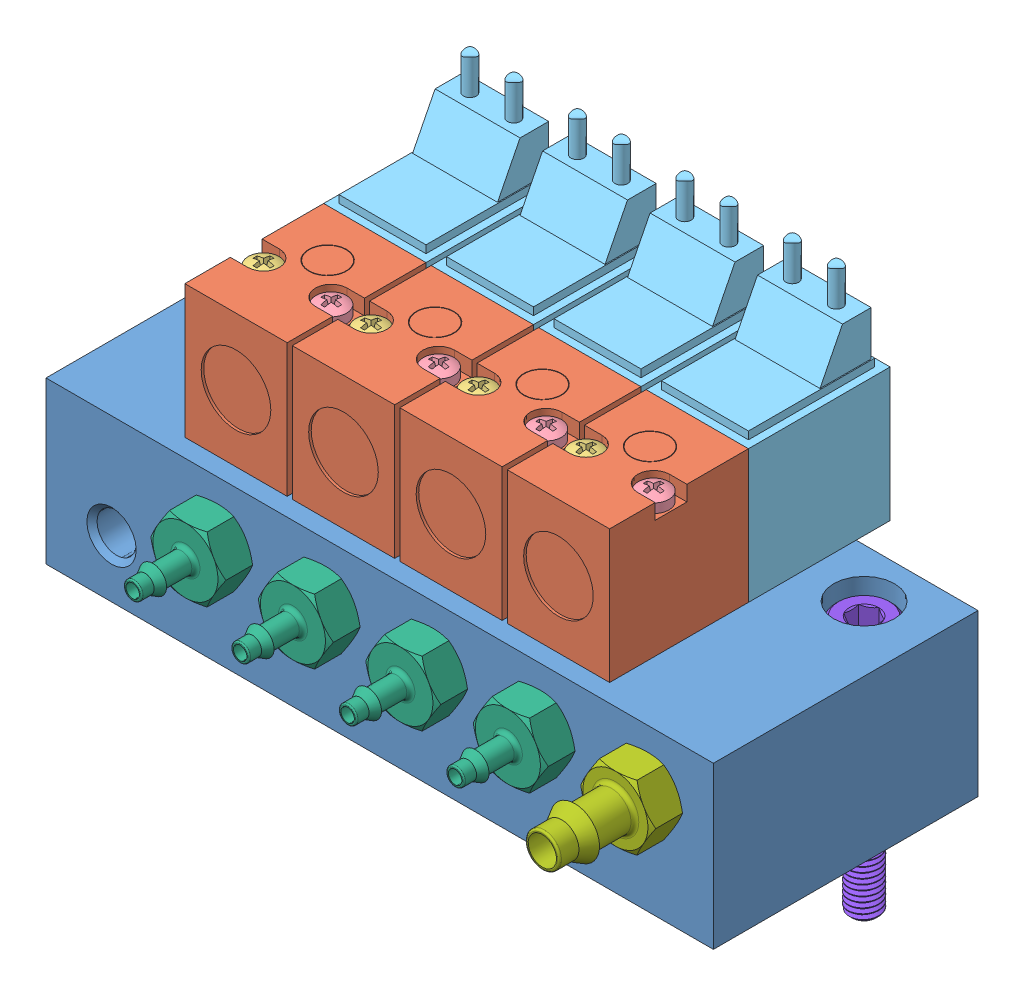
SolidWorks assembly SUB_Solenoid Assembly, configuration Default. Lengths in mm.
Overall size (65.2 48.05 39.48).
28 component instances, 8 part files, 33 mates.
Components (placement in the parent):
- M01_manifold_e10m-04-1: M01_manifold_e10m-04 [Default] at (-10.6613 43.4676 37.3223) x (1 0 0) z (0 -1 0) size (65.2 25.85 15.75)
- M04_valve_e210a-1w012-1: M04_valve_e210a-1w012 [Default] at (6.1387 43.4676 61.4113) x (0 0 -1) z (1 0 0) size (27.4 23.54 10)
  - valve_e210a-1w012_01-1: valve_e210a-1w012_01 [Default] at origin size (15.56 13 10)
  - valve_e210a-1w012_02-1: valve_e210a-1w012_02 [Default] at origin size (3 14.79 3)
  - valve_e210a-1w012_03-1: valve_e210a-1w012_03 [Default] at origin size (3 14.79 3)
  - valve_e210a-1w012_04-1: valve_e210a-1w012_04 [Default] at origin size (13.84 21.54 10)
- M04_valve_e210a-1w012-2: M04_valve_e210a-1w012 [Default] at (16.6387 43.4676 61.4113) x (0 0 -1) z (1 0 0) size (27.4 23.54 10)
  - valve_e210a-1w012_01-1: valve_e210a-1w012_01 [Default] at origin size (15.56 13 10)
  - valve_e210a-1w012_02-1: valve_e210a-1w012_02 [Default] at origin size (3 14.79 3)
  - valve_e210a-1w012_03-1: valve_e210a-1w012_03 [Default] at origin size (3 14.79 3)
  - valve_e210a-1w012_04-1: valve_e210a-1w012_04 [Default] at origin size (13.84 21.54 10)
- M04_valve_e210a-1w012-3: M04_valve_e210a-1w012 [Default] at (27.1387 43.4676 61.4113) x (0 0 -1) z (1 0 0) size (27.4 23.54 10)
  - valve_e210a-1w012_01-1: valve_e210a-1w012_01 [Default] at origin size (15.56 13 10)
  - valve_e210a-1w012_02-1: valve_e210a-1w012_02 [Default] at origin size (3 14.79 3)
  - valve_e210a-1w012_03-1: valve_e210a-1w012_03 [Default] at origin size (3 14.79 3)
  - valve_e210a-1w012_04-1: valve_e210a-1w012_04 [Default] at origin size (13.84 21.54 10)
- M04_valve_e210a-1w012-4: M04_valve_e210a-1w012 [Default] at (37.6387 43.4676 61.4113) x (0 0 -1) z (1 0 0) size (27.4 23.54 10)
  - valve_e210a-1w012_01-1: valve_e210a-1w012_01 [Default] at origin size (15.56 13 10)
  - valve_e210a-1w012_02-1: valve_e210a-1w012_02 [Default] at origin size (3 14.79 3)
  - valve_e210a-1w012_03-1: valve_e210a-1w012_03 [Default] at origin size (3 14.79 3)
  - valve_e210a-1w012_04-1: valve_e210a-1w012_04 [Default] at origin size (13.84 21.54 10)
- M11_11752-5-pkg-2: M11_11752-5-pkg [Default] at (6.1387 38.0176 63.1723) x (0.866025 -0.5 0) z (-0.5 -0.866025 0) size (6.35 12.29 7.33)
- M11_11752-5-pkg-3: M11_11752-5-pkg [Default] at (16.6387 38.0176 63.1723) x (0.866025 -0.5 0) z (-0.5 -0.866025 0) size (6.35 12.29 7.33)
- M11_11752-5-pkg-4: M11_11752-5-pkg [Default] at (37.6387 38.0176 63.1723) x (0.866025 -0.5 0) z (-0.5 -0.866025 0) size (6.35 12.29 7.33)
- M11_11752-5-pkg-5: M11_11752-5-pkg [Default] at (27.1387 38.0176 63.1723) x (0.866025 -0.5 0) z (-0.5 -0.866025 0) size (6.35 12.29 7.33)
- M10_11752-4-pkg-1: M10_11752-4-pkg [Default] at (48.1387 38.0176 66.3473) x (0.866025 0.5 0) z (0.5 -0.866025 0) size (6.35 14.28 7.33)
- 91292A801_18-8 Stainless Steel Socket Head Screw-1: 91292A801_18-8 Stainless Steel Socket Head Screw [91292A801] at (48.1887 29.7076 42.1023) x (1 0 0) z (0 1 0) size (5.5 5.5 25.38)
- 91292A801_18-8 Stainless Steel Socket Head Screw-2: 91292A801_18-8 Stainless Steel Socket Head Screw [91292A801] at (-4.3113 29.7076 42.1023) x (0.5 0 -0.866025) z (0 1 0) size (5.5 5.5 25.38)
Mates (geometry in assembly coordinates):
- Coincident1: coincident anti-aligned: plane of manifold_e10m-04-1 through (21.9387 43.4676 50.2473) normal (0 1 0); plane of valve_e210a-1w012-1/valve_e210a-1w012_01-1 through (6.1387 43.4676 54.6298) normal (0 -1 0)
- Concentric1: concentric aligned: cylinder of manifold_e10m-04-1 through (6.1387 44.4676 54.2683) axis (0 -1 0) radius 0.6; cylinder of valve_e210a-1w012-1/valve_e210a-1w012_01-1 through (6.1387 45.4676 54.2683) axis (0 -1 0) radius 0.6
- Parallel1: parallel aligned: plane of manifold_e10m-04-1 through (21.9387 43.4676 63.1723) normal (0 0 1); plane of valve_e210a-1w012-1/valve_e210a-1w012_01-1 through (6.1387 49.9676 61.4113) normal (0 0 1)
- Concentric2: concentric aligned: cylinder of manifold_e10m-04-1 through (16.6387 44.4676 54.2683) axis (0 -1 0) radius 0.6; cylinder of valve_e210a-1w012-2/valve_e210a-1w012_01-1 through (16.6387 45.4676 54.2683) axis (0 -1 0) radius 0.6
- Coincident3: coincident anti-aligned: plane of manifold_e10m-04-1 through (21.9387 43.4676 50.2473) normal (0 1 0); plane of valve_e210a-1w012-2/valve_e210a-1w012_01-1 through (16.6387 43.4676 54.6298) normal (0 -1 0)
- Parallel2: parallel aligned: plane of manifold_e10m-04-1 through (21.9387 43.4676 63.1723) normal (0 0 1); plane of valve_e210a-1w012-2/valve_e210a-1w012_01-1 through (16.6387 49.9676 61.4113) normal (0 0 1)
- Concentric3: concentric aligned: cylinder of manifold_e10m-04-1 through (27.1387 44.4676 54.2683) axis (0 -1 0) radius 0.6; cylinder of valve_e210a-1w012-3/valve_e210a-1w012_01-1 through (27.1387 45.4676 54.2683) axis (0 -1 0) radius 0.6
- Coincident5: coincident anti-aligned: plane of manifold_e10m-04-1 through (21.9387 43.4676 50.2473) normal (0 1 0); plane of valve_e210a-1w012-3/valve_e210a-1w012_01-1 through (27.1387 43.4676 54.6298) normal (0 -1 0)
- Parallel3: parallel aligned: plane of manifold_e10m-04-1 through (21.9387 43.4676 63.1723) normal (0 0 1); plane of valve_e210a-1w012-3/valve_e210a-1w012_01-1 through (27.1387 49.9676 61.4113) normal (0 0 1)
- Concentric4: concentric aligned: cylinder of manifold_e10m-04-1 through (37.6387 44.4676 54.2683) axis (0 -1 0) radius 0.6; cylinder of valve_e210a-1w012-4/valve_e210a-1w012_01-1 through (37.6387 45.4676 54.2683) axis (0 -1 0) radius 0.6
- Coincident7: coincident anti-aligned: plane of manifold_e10m-04-1 through (21.9387 43.4676 50.2473) normal (0 1 0); plane of valve_e210a-1w012-4/valve_e210a-1w012_01-1 through (37.6387 43.4676 54.6298) normal (0 -1 0)
- Parallel4: parallel aligned: plane of manifold_e10m-04-1 through (21.9387 43.4676 63.1723) normal (0 0 1); plane of valve_e210a-1w012-4/valve_e210a-1w012_01-1 through (37.6387 49.9676 61.4113) normal (0 0 1)
- Concentric5: concentric anti-aligned: cylinder of manifold_e10m-04-1 through (6.1387 38.0176 64.1723) axis (0 0 1) radius 1.915; cylinder of 11752-5-pkg-2 through (6.1387 38.0176 63.1723) axis (0 0 -1) radius 2.3813
- Coincident8: coincident anti-aligned: plane of manifold_e10m-04-1 through (21.9387 43.4676 63.1723) normal (0 0 1); plane of 11752-5-pkg-2 through (7.9717 41.1926 63.1723) normal (0 0 -1)
- Coincident9: coincident anti-aligned: plane of manifold_e10m-04-1 through (21.9387 43.4676 63.1723) normal (0 0 1); plane of 11752-5-pkg-5 through (28.9717 41.1926 63.1723) normal (0 0 -1)
- Coincident10: coincident anti-aligned: plane of manifold_e10m-04-1 through (21.9387 43.4676 63.1723) normal (0 0 1); plane of 11752-5-pkg-3 through (18.4717 41.1926 63.1723) normal (0 0 -1)
- Coincident11: coincident anti-aligned: plane of manifold_e10m-04-1 through (21.9387 43.4676 63.1723) normal (0 0 1); plane of 11752-5-pkg-4 through (39.4717 41.1926 63.1723) normal (0 0 -1)
- Concentric6: concentric anti-aligned: cylinder of manifold_e10m-04-1 through (16.6387 38.0176 64.1723) axis (0 0 1) radius 1.915; cylinder of 11752-5-pkg-3 through (16.6387 38.0176 63.1723) axis (0 0 -1) radius 2.3813
- Concentric7: concentric anti-aligned: cylinder of manifold_e10m-04-1 through (27.1387 38.0176 64.1723) axis (0 0 1) radius 1.915; cylinder of 11752-5-pkg-5 through (27.1387 38.0176 63.1723) axis (0 0 -1) radius 2.3813
- Concentric8: concentric anti-aligned: cylinder of manifold_e10m-04-1 through (37.6387 38.0176 64.1723) axis (0 0 1) radius 1.915; cylinder of 11752-5-pkg-4 through (37.6387 38.0176 63.1723) axis (0 0 -1) radius 2.3813
- Parallel5: parallel aligned: plane of manifold_e10m-04-1 through (21.9387 43.4676 50.2473) normal (0 1 0); plane of 11752-5-pkg-2 through (7.9717 41.1926 66.3473) normal (0 1 0)
- Parallel6: parallel aligned: plane of manifold_e10m-04-1 through (21.9387 43.4676 50.2473) normal (0 1 0); plane of 11752-5-pkg-3 through (18.4717 41.1926 66.3473) normal (0 1 0)
- Parallel7: parallel aligned: plane of manifold_e10m-04-1 through (21.9387 43.4676 50.2473) normal (0 1 0); plane of 11752-5-pkg-5 through (28.9717 41.1926 66.3473) normal (0 1 0)
- Parallel8: parallel aligned: plane of manifold_e10m-04-1 through (21.9387 43.4676 50.2473) normal (0 1 0); plane of 11752-5-pkg-4 through (39.4717 41.1926 66.3473) normal (0 1 0)
- Concentric9: concentric anti-aligned: cylinder of M01_manifold_e10m-04-1 through (48.1387 38.0176 64.1723) axis (0 0 1) radius 1.915; cylinder of M10_11752-4-pkg-1 through (48.1387 38.0176 59.2099) axis (0 0 -1) radius 2.3749
- Coincident12: coincident anti-aligned: plane of M01_manifold_e10m-04-1 through (21.9387 43.4676 63.1723) normal (0 0 1); plane of M10_11752-4-pkg-1 through (53.6379 34.8426 63.1723) normal (0 0 -1)
- Parallel9: parallel aligned: plane of M01_manifold_e10m-04-1 through (21.9387 43.4676 50.2473) normal (0 1 0); plane of M10_11752-4-pkg-1 through (46.3056 41.1926 63.1723) normal (0 1 0)
- Concentric10: concentric anti-aligned: cylinder of M01_manifold_e10m-04-1 through (48.1887 39.2076 42.1023) axis (0 1 0) radius 2.975; cylinder of 91292A801_18-8 Stainless Steel Socket Head Screw-1 through (48.1887 17.2076 42.1023) axis (0 -1 0) radius 2.75
- Coincident13: coincident anti-aligned: plane of M01_manifold_e10m-04-1 through (48.1887 39.2076 42.1023) normal (0 1 0); plane of 91292A801_18-8 Stainless Steel Socket Head Screw-1 through (45.5762 39.2076 42.1023) normal (0 -1 0)
- Parallel10: parallel aligned: plane of M01_manifold_e10m-04-1 through (54.5387 43.4676 50.2473) normal (1 0 0); plane of 91292A801_18-8 Stainless Steel Socket Head Screw-1 through (46.9387 40.3326 41.3806) normal (1 0 0)
- Concentric11: concentric: cylinder of M01_manifold_e10m-04-1 through (-4.3113 39.2076 42.1023) axis (0 1 0) radius 2.975; cylinder of 91292A801_18-8 Stainless Steel Socket Head Screw-2 through (-4.3113 17.2076 42.1023) axis (0 -1 0) radius 2.75
- Coincident15: coincident: plane of M01_manifold_e10m-04-1 through (-4.3113 39.2076 42.1023) normal (0 1 0); plane of 91292A801_18-8 Stainless Steel Socket Head Screw-2 through (-5.6176 39.2076 44.3648) normal (0 -1 0)
- Parallel11: parallel aligned: plane of M01_manifold_e10m-04-1 through (-10.6613 43.4676 50.2473) normal (-1 0 0); plane of 91292A801_18-8 Stainless Steel Socket Head Screw-2 through (-3.0613 40.3326 42.824) normal (-1 0 0)
